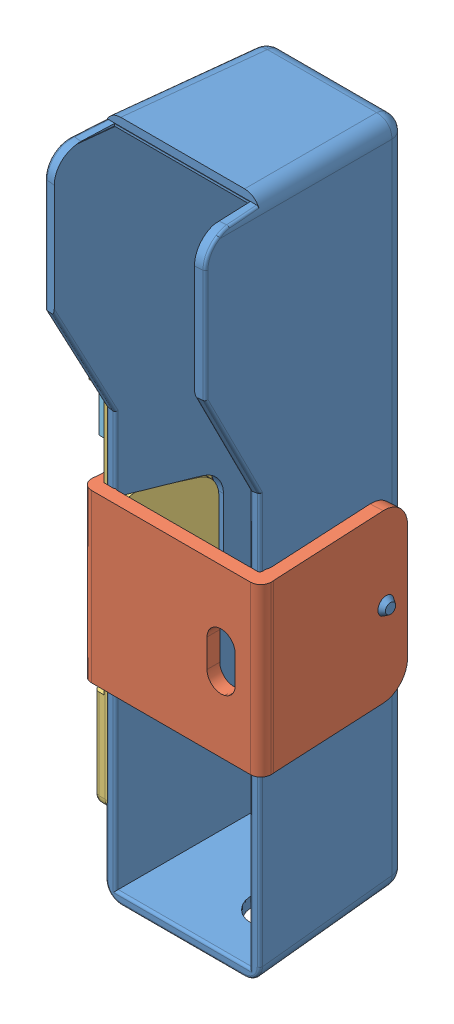
SolidWorks assembly 装配体1, configuration 默认. Lengths in mm.
Overall size (36.08 133.12 41.66).
7 component instances, 5 part files, 9 mates.
Components (placement in the parent):
- 零件1-1: 零件1 [默认] at (-18.2074 -6.1461 133.1176) size (33.41 133.12 41.66)
- 零件4-1: 零件4 [默认] at (-17.9743 -19.1718 163.1176) x (1 0.000001 0) z (0 0 1) size (35 32.5 30)
- 1SD-1: 1SD [默认] at (-33.4283 -48.4995 149.6118) x (0.009061 0 -0.999959) z (-0.999959 0 -0.009061) size (27.15 91.29 6.04)
- SD-1: SD [默认] at (-33.4827 -43.6368 155.6116) x (-0.009061 0 0.999959) z (-0.999959 0 -0.009061) size (11 15 1.13)
- SD-2: SD [默认] at (-33.374 -43.757 143.6121) x (-0.009061 0 0.999959) z (-0.999959 0 -0.009061) size (11 15 1.13)
- 零件2-1: 零件2 [默认] at (-35.4327 14.5246 150.0848) x (-0.009061 0 0.999959) z (0.999959 0 0.009061) size (24 32 2)
- SD-3: SD [默认] at (-32.467 -18.9953 155.9133) x (0 1 0) z (0.99863 0 0.052336) size (11 15 1.13)
Mates (geometry in assembly coordinates):
- 重合3: coincident anti-aligned: plane of 零件1-1 through (-18.2074 -6.1461 163.1176) normal (0 0 1); plane of 零件4-1 through (-17.9743 -19.1718 163.1176) normal (0 0 -1)
- 重合7: coincident: plane of 1SD-1 through (-34.5325 -40.7495 161.1023) normal (0.009061 0 -0.999959); line of SD-1 through (-33.5326 -51.1368 161.1114) axis (0 1 0)
- 重合8: coincident anti-aligned: plane of 1SD-1 through (-34.4283 -48.4995 149.6028) normal (0.999959 0 0.009061); plane of SD-1 through (-34.4827 -43.6368 155.6025) normal (-0.999959 0 -0.009061)
- 重合9: coincident anti-aligned: plane of 1SD-1 through (-34.4283 -48.4995 149.6028) normal (0.999959 0 0.009061); plane of SD-2 through (-34.3739 -43.757 143.603) normal (-0.999959 0 -0.009061)
- 重合10: coincident: plane of 1SD-1 through (-34.3241 -40.7495 138.1033) normal (-0.009061 0 0.999959); line of SD-2 through (-33.3241 -41.257 138.1123) axis (0 1 0)
- 重合11: coincident anti-aligned: plane of 1SD-1 through (-35.4283 -48.4995 149.5937) normal (0.999959 0 0.009061); plane of 零件2-1 through (-35.4327 14.5246 150.0848) normal (-0.999959 0 -0.009061)
- 重合12: coincident anti-aligned: plane of 1SD-1 through (-35.5415 -48.4995 162.0843) normal (0.009061 0 -0.999959); plane of 零件2-1 through (-33.5415 30.5246 162.1024) normal (-0.009061 0 0.999959)
- 重合15: coincident anti-aligned: plane of 1SD-1 through (-32.1403 -48.4995 149.6793) normal (0.99863 0 0.052336); plane of SD-3 through (-32.467 -18.9953 155.9133) normal (-0.99863 0 -0.052336)
- 重合16: coincident anti-aligned: plane of 1SD-1 through (-32.8457 -13.4953 163.1393) normal (0 -1 0); plane of SD-3 through (-31.4684 -13.4953 155.9656) normal (0 1 0)
